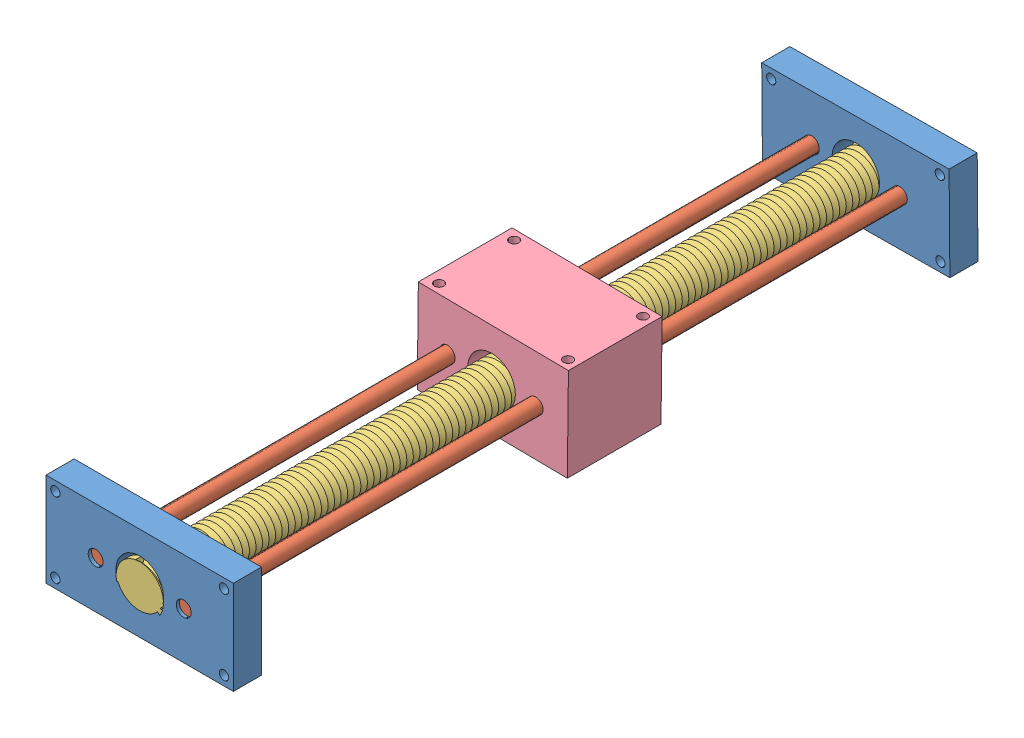
SolidWorks assembly Ensamblaje bueno 1.2, configuration Predeterminado. Lengths in mm.
Overall size (100.42 51.46 404.86).
6 component instances, 4 part files, 7 mates.
Components (placement in the parent):
- Pieza1-1: Pieza1 [Predeterminado] at (20.4053 -20.4669 100) size (100 50 15)
- Pieza2-3: Pieza2 [Predeterminado] at (-19.9491 4.5331 -286.8033) x (0.666646 -0.745374 0) z (0 0 1) size (8 8 400)
- Esparrago 40 cm-3: Esparrago 40 cm [Predeterminado] at (3.8089 2.3936 -285) x (0 0 1) z (0.999111 -0.042152 0) size (404.86 26.06 26.06)
- Pieza2-4: Pieza2 [Predeterminado] at (27.0509 4.5331 -286.6261) x (0.873737 -0.486398 0) z (0 0 1) size (8 8 400)
- Base CNC 1-1: Base CNC 1 [Predeterminado] at (33.2507 -2.0707 -72.7816) x (-0.999932 0.011655 0) z (0 0 -1) size (80.09 50.06 50)
- Pieza1-2: Pieza1 [Predeterminado] at (20.6186 -20.5227 -282.1417) x (0.999964 0.008525 0) z (0 0 1) size (100 50 15)
Mates (geometry in assembly coordinates):
- Concéntrica3: concentric: circle of assembly; cylinder of assembly; circle of Pieza1-1; cylinder of Pieza2-3 through (-19.9491 4.5331 113.1967) axis (0 0 -1) radius 4
- Coincidente10: coincident: plane of assembly; plane of assembly; plane of Pieza1-1 through (20.4053 -20.4669 115) normal (0 0 1); plane of Esparrago 40 cm-3 through (3.6057 1.8601 115) normal (0 0 1)
- Concéntrica4: concentric: circle of assembly; cylinder of assembly; circle of Pieza1-1; cylinder of Pieza2-4 through (27.0509 4.5331 113.3739) axis (0 0 -1) radius 4
- Concéntrica5: concentric: cylinder of assembly; circle of assembly; cylinder of Pieza2-4 through (27.0509 4.5331 113.3739) axis (0 0 -1) radius 4; circle of Base CNC 1-1
- Paralelo2: parallel: cylinder of assembly; cylinder of assembly; cylinder of Pieza2-3 through (-19.9491 4.5331 113.1967) axis (0 0 -1) radius 4; cylinder of Base CNC 1-1 through (-19.9435 4.9551 -122.7816) axis (0 0 1) radius 4.0047
- Tangente27: tangent: circle of assembly; face of Esparrago 40 cm-3; circle of Base CNC 1-1
- Coincidente13: coincident: cylinder of assembly; circle of assembly; cylinder of Pieza2-4 through (27.0509 4.5331 113.3739) axis (0 0 -1) radius 4; circle of Pieza1-2
